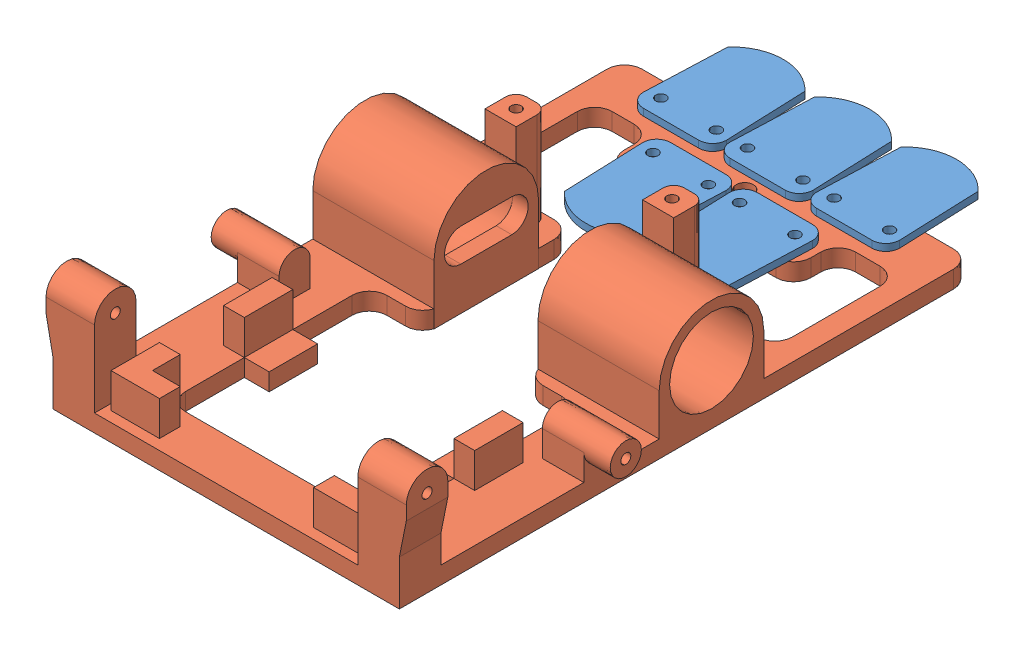
SolidWorks assembly Assem2, configuration Default. Lengths in mm.
Overall size (115.2 33 185.84).
6 component instances, 2 part files, 15 mates.
Components (placement in the parent):
- SENSOR-1: SENSOR [Default] at (-117.1321 -4.6904 -59.6054) x (-1 0 0) z (0 0 -1) size (24 2 32.42)
- SENSOR-2: SENSOR [Default] at (-67.1321 -4.6904 -59.6054) x (-1 0 0) z (0 0 -1) size (24 2 32.42)
- SENSOR-3: SENSOR [Default] at (-92.1321 -4.6904 -59.6054) x (-1 0 0) z (0 0 -1) size (24 2 32.42)
- SENSOR-4: SENSOR [Default] at (-79.6321 -4.6904 -46.9654) size (24 2 32.42)
- SENSOR-5: SENSOR [Default] at (-104.6321 -4.6904 -46.9654) size (24 2 32.42)
- BODY 3-2: BODY 3 [Default] at (-92.1321 -9.6904 -2.1854) size (115.2 33 165)
Mates (geometry in assembly coordinates):
- Coincident25: coincident anti-aligned: plane of SENSOR-4 through (-87.6321 -4.6904 -46.9654) normal (0 -1 0); plane of BODY 3-2 through (-92.1321 -4.6904 -2.1854) normal (0 1 0)
- Coincident26: coincident anti-aligned: plane of SENSOR-5 through (-112.6321 -4.6904 -46.9654) normal (0 -1 0); plane of BODY 3-2 through (-92.1321 -4.6904 -2.1854) normal (0 1 0)
- Coincident27: coincident anti-aligned: plane of SENSOR-1 through (-109.1321 -4.6904 -59.6054) normal (0 -1 0); plane of BODY 3-2 through (-92.1321 -4.6904 -2.1854) normal (0 1 0)
- Coincident28: coincident anti-aligned: plane of SENSOR-3 through (-84.1321 -4.6904 -59.6054) normal (0 -1 0); plane of BODY 3-2 through (-92.1321 -4.6904 -2.1854) normal (0 1 0)
- Coincident29: coincident anti-aligned: plane of SENSOR-2 through (-59.1321 -4.6904 -59.6054) normal (0 -1 0); plane of BODY 3-2 through (-92.1321 -4.6904 -2.1854) normal (0 1 0)
- Concentric27: concentric anti-aligned: cylinder of SENSOR-4 through (-87.6321 -2.6904 -45.8854) axis (0 -1 0) radius 1.5; cylinder of BODY 3-2 through (-87.6321 -14.6904 -45.8854) axis (0 1 0) radius 1.5
- Coincident30: coincident anti-aligned: cylinder of SENSOR-4 through (-71.6321 -2.6904 -45.8854) axis (0 -1 0) radius 1.5; circle of BODY 3-2
- Coincident31: coincident aligned: circle of SENSOR-5; cylinder of BODY 3-2 through (-96.6321 -14.6904 -45.8854) axis (0 1 0) radius 1.5
- Coincident32: coincident aligned: circle of SENSOR-5; cylinder of BODY 3-2 through (-112.6321 -14.6904 -45.8854) axis (0 1 0) radius 1.5
- Coincident33: coincident aligned: circle of SENSOR-1; cylinder of BODY 3-2 through (-109.1321 -9.6914 -60.6854) axis (0 1 0) radius 1.5
- Coincident34: coincident aligned: circle of SENSOR-1; cylinder of BODY 3-2 through (-125.1321 -9.6914 -60.6854) axis (0 1 0) radius 1.5
- Coincident38: coincident aligned: circle of SENSOR-3; cylinder of BODY 3-2 through (-84.1321 -9.6914 -60.6854) axis (0 1 0) radius 1.5
- Coincident39: coincident aligned: circle of SENSOR-3; cylinder of BODY 3-2 through (-100.1321 -9.6914 -60.6854) axis (0 1 0) radius 1.5
- Coincident40: coincident aligned: circle of SENSOR-2; cylinder of BODY 3-2 through (-59.1321 -9.6914 -60.6854) axis (0 1 0) radius 1.5
- Concentric28: concentric anti-aligned: cylinder of SENSOR-2 through (-75.1321 -2.6904 -60.6854) axis (0 -1 0) radius 1.5; cylinder of BODY 3-2 through (-75.1321 -9.6914 -60.6854) axis (0 1 0) radius 1.5
